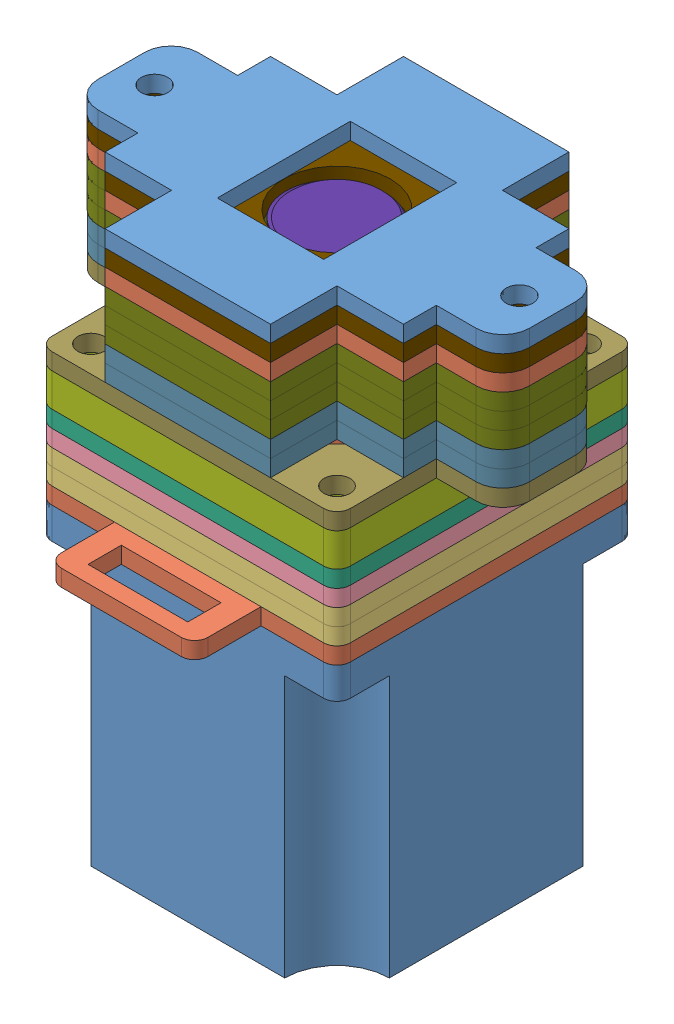
SolidWorks assembly Gearbox, configuration Default. Lengths in mm.
Overall size (82.4 106.8 74.43).
32 component instances, 20 part files, 82 mates.
Components (placement in the parent):
- Stepper-2: Stepper [Default] at (30.9949 23.0878 37.3572) size (57 78.6 57)
- Bottomest Layer-1: Bottomest Layer [Default] at (30.9949 79.0878 37.3572) x (0 0 -1) z (1 0 0) size (69.7 3.17 57)
- Bottom Layer-1: Bottom Layer [Default] at (30.9949 82.2628 37.3572) size (57 3.17 57)
- Bottom Layer-2: Bottom Layer [Default] at (30.9949 85.4378 37.3572) size (57 3.17 57)
- Bottom Middle Layer-1: Bottom Middle Layer [Default] at (30.9949 88.6128 37.3572) size (57 3.17 57)
- Bottom Planet Retainer-1: Bottom Planet Retainer [Default] at (30.9949 91.7878 37.3572) size (50.8 3.17 50.8)
- Bottom Planet Retainer Layer-1: Bottom Planet Retainer Layer [Default] at (30.9949 91.7878 37.3572) size (57 3.17 57)
- Gear-64-1: Gear-64 [Default] at (121.5885 94.9628 50.1488) size (57 6.35 57)
- Gear-24-New-1: Gear-24-New [Default] at (71.8801 101.3128 34.4101) x (1 0 0) z (0 -1 0) size (20.51 20.51 6.35)
- Gear-24-New-2: Gear-24-New [Default] at (87.5193 101.3128 50.0415) x (1 0 0) z (0 -1 0) size (20.51 20.51 6.35)
- Gear-24-New-3: Gear-24-New [Default] at (71.8878 101.3128 65.6808) x (1 0 0) z (0 -1 0) size (20.51 20.51 6.35)
- Gear-24-New-4: Gear-24-New [Default] at (56.2486 101.3128 50.0493) x (1 0 0) z (0 -1 0) size (20.51 20.51 6.35)
- Gear-16-1: Gear-16 [Default] at (42.6663 94.9628 47.2863) x (-1 0 0) z (0 0 -1) size (14.29 6.35 14.29)
- Planet Axle-1: Planet Axle [Default] at (15.3596 94.9628 37.3611) x (0.999996 0 0.002972) z (-0.002972 0 0.999996) size (7.62 9.53 7.62)
- Planet Axle-2: Planet Axle [Default] at (30.991 94.9628 21.7218) x (0.999983 0 0.005817) z (-0.005817 0 0.999983) size (7.62 9.53 7.62)
- Planet Axle-3: Planet Axle [Default] at (46.6303 94.9628 37.3533) x (0.999937 0 -0.011253) z (0.011253 0 0.999937) size (7.62 9.53 7.62)
- Planet Axle-4: Planet Axle [Default] at (30.9988 94.9628 52.9925) x (0.999998 0 -0.001861) z (0.001861 0 0.999998) size (7.62 9.53 7.62)
- Planet Retainer-1: Planet Retainer [Default] at (30.9949 101.3128 37.3572) x (0.706931 0 -0.707283) z (0.707283 0 0.706931) size (46.99 3.17 46.99)
- Middle Layer-1: Middle Layer [Default] at (30.9949 101.3128 37.3572) size (82.4 3.17 57)
- Valve Shaft Engage-1: Valve Shaft Engage [Default] at (30.9949 104.4878 37.3572) x (0.992527 0 -0.122022) z (0.122022 0 0.992527) size (25.4 3.17 25.4)
- Valve Engage Retainer Layer-1: Valve Engage Retainer Layer [Default] at (30.9949 104.4878 37.3572) size (82.4 3.17 57)
- Valve Engage Retainer Layer-2: Valve Engage Retainer Layer [Default] at (30.9949 107.6628 37.3572) size (82.4 3.17 57)
- Valve Shaft Engage Retainer-1: Valve Shaft Engage Retainer [Default] at (30.9949 104.4878 37.3572) size (45.72 3.17 45.72)
- Valve Shaft Engage Retainer-2: Valve Shaft Engage Retainer [Default] at (30.9949 107.6628 37.3572) size (45.72 3.17 45.72)
- Valve Shaft Engage-2: Valve Shaft Engage [Default] at (30.9949 107.6628 37.3572) x (0.992527 0 -0.122022) z (0.122022 0 0.992527) size (25.4 3.17 25.4)
- Top Layer - Valve-2: Top Layer - Valve [Default] at (30.9949 110.8378 37.3572) size (82.4 3.17 57)
- Valve-1: Valve [Default] at (30.9949 112.7617 37.3572) x (-0.992527 0 0.122022) z (0.122022 0 0.992527) size (19.14 21.75 19.92)
- Top Layer - Valve-3: Top Layer - Valve [Default] at (30.9949 114.0128 37.3572) size (82.4 3.17 57)
- Top Layer - Valve-4: Top Layer - Valve [Default] at (30.9949 117.1878 37.3572) size (82.4 3.17 57)
- Top Layer - Valve Interface-1: Top Layer - Valve Interface [Default] at (30.9949 123.5378 37.3572) size (82.4 3.17 57)
- Top Layer - Valve Rotate Lock-1: Top Layer - Valve Rotate Lock [Default] at (30.9949 126.7128 37.3572) size (82.4 3.17 57)
- Top Layer - Valve Nut Lock-1: Top Layer - Valve Nut Lock [Default] at (30.9949 120.3628 37.3572) size (82.4 3.17 57)
Mates (geometry in assembly coordinates):
- Concentric2: concentric anti-aligned: cylinder of Stepper-2 through (54.4949 53.6878 60.8572) axis (0 1 0) radius 2.5; cylinder of Bottomest Layer-1 through (54.4949 82.2628 60.8572) axis (0 -1 0) radius 2.5
- Concentric3: concentric anti-aligned: cylinder of Stepper-2 through (7.4949 53.6878 60.8572) axis (0 1 0) radius 2.5; cylinder of Bottomest Layer-1 through (7.4949 82.2628 60.8572) axis (0 -1 0) radius 2.5
- Concentric7: concentric aligned: cylinder of Bottomest Layer-1 through (54.4949 82.2628 60.8572) axis (0 -1 0) radius 2.5; cylinder of Bottom Layer-1 through (54.4949 85.4378 60.8572) axis (0 -1 0) radius 2.5
- Concentric8: concentric aligned: cylinder of Bottomest Layer-1 through (7.4949 82.2628 60.8572) axis (0 -1 0) radius 2.5; cylinder of Bottom Layer-1 through (7.4949 85.4378 60.8572) axis (0 -1 0) radius 2.5
- Concentric9: concentric aligned: cylinder of Bottom Layer-1 through (7.4949 85.4378 60.8572) axis (0 -1 0) radius 2.5; cylinder of Bottom Layer-2 through (7.4949 88.6128 60.8572) axis (0 -1 0) radius 2.5
- Concentric10: concentric aligned: cylinder of Bottom Layer-1 through (54.4949 85.4378 60.8572) axis (0 -1 0) radius 2.5; cylinder of Bottom Layer-2 through (54.4949 88.6128 60.8572) axis (0 -1 0) radius 2.5
- Coincident1: coincident anti-aligned: plane of Stepper-2 through (30.9949 79.0878 37.3572) normal (0 1 0); plane of Bottomest Layer-1 through (5.0349 79.0878 11.3972) normal (0 -1 0)
- Coincident2: coincident anti-aligned: plane of Bottomest Layer-1 through (5.0349 82.2628 11.3972) normal (0 1 0); plane of Bottom Layer-1 through (56.9549 82.2628 11.3972) normal (0 -1 0)
- Coincident3: coincident anti-aligned: plane of Bottom Layer-1 through (56.9549 85.4378 11.3972) normal (0 1 0); plane of Bottom Layer-2 through (56.9549 85.4378 11.3972) normal (0 -1 0)
- Concentric11: concentric aligned: cylinder of Bottom Layer-2 through (7.4949 88.6128 60.8572) axis (0 -1 0) radius 2.5; cylinder of Bottom Middle Layer-1 through (7.4949 91.7878 60.8572) axis (0 -1 0) radius 2.5
- Concentric12: concentric aligned: cylinder of Bottom Layer-2 through (54.4949 88.6128 60.8572) axis (0 -1 0) radius 2.5; cylinder of Bottom Middle Layer-1 through (54.4949 91.7878 60.8572) axis (0 -1 0) radius 2.5
- Coincident5: coincident anti-aligned: plane of Bottom Layer-2 through (56.9549 88.6128 11.3972) normal (0 1 0); plane of Bottom Middle Layer-1 through (56.9549 88.6128 11.3972) normal (0 -1 0)
- Concentric13: concentric aligned: cylinder of Bottom Middle Layer-1 through (54.4949 91.7878 60.8572) axis (0 -1 0) radius 2.5; cylinder of Bottom Planet Retainer Layer-1 through (54.4949 94.9628 60.8572) axis (0 -1 0) radius 2.5
- Concentric14: concentric aligned: cylinder of Bottom Middle Layer-1 through (7.4949 91.7878 60.8572) axis (0 -1 0) radius 2.5; cylinder of Bottom Planet Retainer Layer-1 through (7.4949 94.9628 60.8572) axis (0 -1 0) radius 2.5
- Coincident6: coincident anti-aligned: plane of Bottom Planet Retainer-1 through (9.0047 94.9628 54.883) normal (-0.706647 0 0.707566); plane of Bottom Planet Retainer Layer-1 through (9.0047 94.9628 54.883) normal (0.706647 0 -0.707566)
- Coincident7: coincident anti-aligned: plane of Bottom Planet Retainer-1 through (48.5207 94.9628 59.3474) normal (0.707566 0 0.706647); plane of Bottom Planet Retainer Layer-1 through (48.5207 94.9628 59.3474) normal (-0.707566 0 -0.706647)
- Coincident8: coincident aligned: plane of Bottom Planet Retainer-1 through (30.9949 94.9628 37.3572) normal (0 1 0); plane of Bottom Planet Retainer Layer-1 through (56.9549 94.9628 11.3972) normal (0 1 0)
- Coincident9: coincident anti-aligned: plane of Bottom Middle Layer-1 through (56.9549 91.7878 11.3972) normal (0 1 0); plane of Bottom Planet Retainer Layer-1 through (56.9549 91.7878 11.3972) normal (0 -1 0)
- Concentric16: concentric aligned: cylinder of Bottom Planet Retainer Layer-1 through (7.4949 94.9628 60.8572) axis (0 -1 0) radius 2.5; cylinder of Gear-64-1 through (7.4949 101.3128 60.8572) axis (0 -1 0) radius 2.5
- Concentric17: concentric aligned: cylinder of Bottom Planet Retainer Layer-1 through (54.4949 94.9628 60.8572) axis (0 -1 0) radius 2.5; cylinder of Gear-64-1 through (54.4949 101.3128 60.8572) axis (0 -1 0) radius 2.5
- Coincident10: coincident anti-aligned: plane of Bottom Planet Retainer Layer-1 through (56.9549 94.9628 11.3972) normal (0 1 0); plane of Gear-64-1 through (5.0349 94.9628 63.3172) normal (0 -1 0)
- Coincident17: coincident aligned: plane of Gear-64-1 through (5.0349 101.3128 63.3172) normal (0 1 0); plane of Gear-24-New-4 through (13.2871 101.3128 33.3946) normal (0 1 0)
- Coincident18: coincident aligned: plane of Gear-64-1 through (5.0349 101.3128 63.3172) normal (0 1 0); plane of Gear-24-New-1 through (28.9185 101.3128 17.7553) normal (0 1 0)
- Coincident19: coincident aligned: plane of Gear-64-1 through (5.0349 101.3128 63.3172) normal (0 1 0); plane of Gear-24-New-2 through (44.5578 101.3128 33.3868) normal (0 1 0)
- Coincident20: coincident aligned: plane of Gear-64-1 through (5.0349 101.3128 63.3172) normal (0 1 0); plane of Gear-24-New-3 through (28.9263 101.3128 49.0261) normal (0 1 0)
- Coincident21: coincident anti-aligned: plane of Stepper-2 through (32.7052 86.6878 40.0322) normal (0 0 1); plane of Gear-16-1 through (32.7052 101.3128 40.0322) normal (0 0 -1)
- Concentric18: concentric aligned: cylinder of Stepper-2 through (30.9949 101.6878 37.3572) axis (0 -1 0) radius 3.175; cylinder of Gear-16-1 through (30.9949 101.3128 37.3572) axis (0 -1 0) radius 3.175
- Coincident22: coincident aligned: plane of Gear-64-1 through (5.0349 101.3128 63.3172) normal (0 1 0); plane of Gear-16-1 through (31.1794 101.3128 34.3794) normal (0 1 0)
- Concentric19: concentric anti-aligned: cylinder of Gear-24-New-4 through (15.3596 94.9628 37.3611) axis (0 1 0) radius 3.81; cylinder of Planet Axle-1 through (15.3596 104.4878 37.3611) axis (0 -1 0) radius 3.81
- Concentric20: concentric anti-aligned: cylinder of Gear-24-New-1 through (30.991 94.9628 21.7218) axis (0 1 0) radius 3.81; cylinder of Planet Axle-2 through (30.991 104.4878 21.7218) axis (0 -1 0) radius 3.81
- Concentric21: concentric anti-aligned: cylinder of Gear-24-New-2 through (46.6303 94.9628 37.3533) axis (0 1 0) radius 3.81; cylinder of Planet Axle-3 through (46.6303 104.4878 37.3533) axis (0 -1 0) radius 3.81
- Concentric22: concentric anti-aligned: cylinder of Gear-24-New-3 through (30.9988 94.9628 52.9925) axis (0 1 0) radius 3.81; cylinder of Planet Axle-4 through (30.9988 104.4878 52.9925) axis (0 -1 0) radius 3.81
- Coincident23: coincident anti-aligned: plane of Bottom Planet Retainer-1 through (30.9949 94.9628 37.3572) normal (0 1 0); plane of Planet Axle-1 through (15.3596 94.9628 37.3611) normal (0 -1 0)
- Coincident24: coincident anti-aligned: plane of Bottom Planet Retainer-1 through (30.9949 94.9628 37.3572) normal (0 1 0); plane of Planet Axle-4 through (30.9988 94.9628 52.9925) normal (0 -1 0)
- Coincident25: coincident anti-aligned: plane of Bottom Planet Retainer-1 through (30.9949 94.9628 37.3572) normal (0 1 0); plane of Planet Axle-3 through (46.6303 94.9628 37.3533) normal (0 -1 0)
- Coincident26: coincident anti-aligned: plane of Bottom Planet Retainer-1 through (30.9949 94.9628 37.3572) normal (0 1 0); plane of Planet Axle-2 through (30.991 94.9628 21.7218) normal (0 -1 0)
- Concentric23: concentric aligned: cylinder of Stepper-2 through (30.9949 101.6878 37.3572) axis (0 -1 0) radius 3.175; cylinder of Planet Retainer-1 through (30.9949 104.4878 37.3572) axis (0 -1 0) radius 3.556
- Coincident27: coincident anti-aligned: plane of Gear-64-1 through (5.0349 101.3128 63.3172) normal (0 1 0); plane of Planet Retainer-1 through (30.9949 101.3128 37.3572) normal (0 -1 0)
- Concentric24: concentric aligned: cylinder of Planet Axle-1 through (15.3596 104.4878 37.3611) axis (0 -1 0) radius 3.81; cylinder of Planet Retainer-1 through (15.3596 104.4878 37.3611) axis (0 -1 0) radius 3.81
- Concentric25: concentric aligned: cylinder of Planet Axle-2 through (30.991 104.4878 21.7218) axis (0 -1 0) radius 3.81; cylinder of Planet Retainer-1 through (30.991 104.4878 21.7218) axis (0 -1 0) radius 3.81
- Concentric26: concentric aligned: cylinder of Planet Axle-3 through (46.6303 104.4878 37.3533) axis (0 -1 0) radius 3.81; cylinder of Planet Retainer-1 through (46.6303 104.4878 37.3533) axis (0 -1 0) radius 3.81
- Concentric27: concentric aligned: cylinder of Planet Axle-4 through (30.9988 104.4878 52.9925) axis (0 -1 0) radius 3.81; cylinder of Planet Retainer-1 through (30.9988 104.4878 52.9925) axis (0 -1 0) radius 3.81
- Concentric28: concentric aligned: cylinder of Gear-64-1 through (7.4949 101.3128 60.8572) axis (0 -1 0) radius 2.5; cylinder of Middle Layer-1 through (7.4949 104.4878 60.8572) axis (0 -1 0) radius 2.5
- Concentric29: concentric aligned: cylinder of Gear-64-1 through (54.4949 101.3128 60.8572) axis (0 -1 0) radius 2.5; cylinder of Middle Layer-1 through (54.4949 104.4878 60.8572) axis (0 -1 0) radius 2.5
- Coincident28: coincident anti-aligned: plane of Gear-64-1 through (5.0349 101.3128 63.3172) normal (0 1 0); plane of Middle Layer-1 through (56.9549 101.3128 11.3972) normal (0 -1 0)
- Concentric30: concentric anti-aligned: circle of Planet Retainer-1; cylinder of Valve Shaft Engage-1 through (30.9949 107.6628 37.3572) axis (0 -1 0) radius 2.6
- Coincident29: coincident anti-aligned: plane of Planet Retainer-1 through (30.9949 104.4878 37.3572) normal (0 1 0); plane of Valve Shaft Engage-1 through (30.9949 104.4878 37.3572) normal (0 -1 0)
- Concentric31: concentric aligned: cylinder of Middle Layer-1 through (-3.8551 104.4878 37.3572) axis (0 -1 0) radius 2.54; cylinder of Valve Engage Retainer Layer-1 through (-3.8551 107.6628 37.3572) axis (0 -1 0) radius 2.54
- Concentric32: concentric aligned: cylinder of Middle Layer-1 through (65.8449 104.4878 37.3572) axis (0 -1 0) radius 2.54; cylinder of Valve Engage Retainer Layer-1 through (65.8449 107.6628 37.3572) axis (0 -1 0) radius 2.54
- Coincident30: coincident anti-aligned: plane of Middle Layer-1 through (56.9549 104.4878 11.3972) normal (0 1 0); plane of Valve Engage Retainer Layer-1 through (-5.1251 104.4878 32.9122) normal (0 -1 0)
- Coincident31: coincident anti-aligned: plane of Valve Engage Retainer Layer-1 through (34.1699 107.6628 60.2172) normal (0 0 -1); plane of Valve Shaft Engage Retainer-1 through (34.1699 107.6628 60.2172) normal (0 0 1)
- Coincident32: coincident anti-aligned: plane of Valve Engage Retainer Layer-1 through (8.1349 107.6628 40.5322) normal (1 0 0); plane of Valve Shaft Engage Retainer-1 through (8.1349 107.6628 40.5322) normal (-1 0 0)
- Coincident33: coincident anti-aligned: plane of Planet Retainer-1 through (30.9949 104.4878 37.3572) normal (0 1 0); plane of Valve Shaft Engage Retainer-1 through (30.9949 104.4878 37.3572) normal (0 -1 0)
- Concentric33: concentric aligned: cylinder of Valve Engage Retainer Layer-1 through (-3.8551 107.6628 37.3572) axis (0 -1 0) radius 2.54; cylinder of Valve Engage Retainer Layer-2 through (-3.8551 110.8378 37.3572) axis (0 -1 0) radius 2.54
- Concentric34: concentric aligned: cylinder of Valve Engage Retainer Layer-1 through (65.8449 107.6628 37.3572) axis (0 -1 0) radius 2.54; cylinder of Valve Engage Retainer Layer-2 through (65.8449 110.8378 37.3572) axis (0 -1 0) radius 2.54
- Coincident34: coincident anti-aligned: plane of Valve Engage Retainer Layer-1 through (-5.1251 107.6628 32.9122) normal (0 1 0); plane of Valve Engage Retainer Layer-2 through (-5.1251 107.6628 32.9122) normal (0 -1 0)
- Coincident36: coincident anti-aligned: plane of Valve Engage Retainer Layer-2 through (34.1699 110.8378 60.2172) normal (0 0 -1); plane of Valve Shaft Engage Retainer-2 through (34.1699 110.8378 60.2172) normal (0 0 1)
- Coincident37: coincident anti-aligned: plane of Valve Engage Retainer Layer-2 through (8.1349 110.8378 40.5322) normal (1 0 0); plane of Valve Shaft Engage Retainer-2 through (8.1349 110.8378 40.5322) normal (-1 0 0)
- Coincident38: coincident anti-aligned: plane of Valve Shaft Engage Retainer-1 through (30.9949 107.6628 37.3572) normal (0 1 0); plane of Valve Shaft Engage Retainer-2 through (30.9949 107.6628 37.3572) normal (0 -1 0)
- Coincident39: coincident aligned: plane of Valve Shaft Engage-1 through (29.0455 107.6628 35.6369) normal (0.122022 0 0.992527); plane of Valve Shaft Engage-2 through (29.0455 110.8378 35.6369) normal (0.122022 0 0.992527)
- Concentric35: concentric aligned: cylinder of Valve Shaft Engage-1 through (30.9949 107.6628 37.3572) axis (0 -1 0) radius 2.6; cylinder of Valve Shaft Engage-2 through (30.9949 110.8378 37.3572) axis (0 -1 0) radius 2.6
- Coincident40: coincident anti-aligned: plane of Valve Shaft Engage-1 through (30.9949 107.6628 37.3572) normal (0 1 0); plane of Valve Shaft Engage-2 through (30.9949 107.6628 37.3572) normal (0 -1 0)
- Concentric36: concentric aligned: cylinder of Valve Engage Retainer Layer-2 through (-3.8551 110.8378 37.3572) axis (0 -1 0) radius 2.54; cylinder of Top Layer - Valve-2 through (-3.8551 114.0128 37.3572) axis (0 -1 0) radius 2.54
- Concentric37: concentric aligned: cylinder of Valve Engage Retainer Layer-2 through (65.8449 110.8378 37.3572) axis (0 -1 0) radius 2.54; cylinder of Top Layer - Valve-2 through (65.8449 114.0128 37.3572) axis (0 -1 0) radius 2.54
- Coincident41: coincident anti-aligned: plane of Valve Engage Retainer Layer-2 through (-5.1251 110.8378 32.9122) normal (0 1 0); plane of Top Layer - Valve-2 through (-5.1251 110.8378 32.9122) normal (0 -1 0)
- Coincident42: coincident anti-aligned: plane of Valve Shaft Engage-2 through (29.8623 110.8378 39.6975) normal (-0.122022 0 -0.992527); plane of Valve-1 through (32.6607 104.7617 39.3535) normal (0.122022 0 0.992527)
- Concentric38: concentric anti-aligned: cylinder of Valve Shaft Engage-2 through (30.9949 110.8378 37.3572) axis (0 -1 0) radius 2.6; cylinder of Valve-1 through (30.9949 104.7617 37.3572) axis (0 1 0) radius 2.6
- Concentric39: concentric aligned: cylinder of Top Layer - Valve-2 through (-3.8551 114.0128 37.3572) axis (0 -1 0) radius 2.54; cylinder of Top Layer - Valve-3 through (-3.8551 117.1878 37.3572) axis (0 -1 0) radius 2.54
- Concentric40: concentric aligned: cylinder of Top Layer - Valve-2 through (65.8449 114.0128 37.3572) axis (0 -1 0) radius 2.54; cylinder of Top Layer - Valve-3 through (65.8449 117.1878 37.3572) axis (0 -1 0) radius 2.54
- Coincident43: coincident anti-aligned: plane of Top Layer - Valve-2 through (-5.1251 114.0128 32.9122) normal (0 1 0); plane of Top Layer - Valve-3 through (-5.1251 114.0128 32.9122) normal (0 -1 0)
- Coincident44: coincident anti-aligned: plane of Top Layer - Valve-3 through (-5.1251 117.1878 32.9122) normal (0 1 0); plane of Top Layer - Valve-4 through (-5.1251 117.1878 32.9122) normal (0 -1 0)
- Concentric41: concentric aligned: cylinder of Top Layer - Valve-3 through (65.8449 117.1878 37.3572) axis (0 -1 0) radius 2.54; cylinder of Top Layer - Valve-4 through (65.8449 120.3628 37.3572) axis (0 -1 0) radius 2.54
- Concentric42: concentric aligned: cylinder of Top Layer - Valve-3 through (-3.8551 117.1878 37.3572) axis (0 -1 0) radius 2.54; cylinder of Top Layer - Valve-4 through (-3.8551 120.3628 37.3572) axis (0 -1 0) radius 2.54
- Concentric47: concentric aligned: cylinder of Top Layer - Valve Interface-1 through (-3.8551 152.7697 37.3572) axis (0 -1 0) radius 2.54; cylinder of Top Layer - Valve Rotate Lock-1 through (-3.8551 155.9447 37.3572) axis (0 -1 0) radius 2.54
- Concentric48: concentric aligned: cylinder of Top Layer - Valve Interface-1 through (65.8449 152.7697 37.3572) axis (0 -1 0) radius 2.54; cylinder of Top Layer - Valve Rotate Lock-1 through (65.8449 155.9447 37.3572) axis (0 -1 0) radius 2.54
- Coincident47: coincident anti-aligned: plane of Top Layer - Valve Interface-1 through (-5.1251 152.7697 32.9122) normal (0 1 0); plane of Top Layer - Valve Rotate Lock-1 through (-5.1251 152.7697 32.9122) normal (0 -1 0)
- Concentric49: concentric aligned: cylinder of Top Layer - Valve-4 through (-3.8551 120.3628 37.3572) axis (0 -1 0) radius 2.54; cylinder of Top Layer - Valve Nut Lock-1 through (-3.8551 123.5378 37.3572) axis (0 -1 0) radius 2.54
- Concentric50: concentric aligned: cylinder of Top Layer - Valve-4 through (65.8449 120.3628 37.3572) axis (0 -1 0) radius 2.54; cylinder of Top Layer - Valve Nut Lock-1 through (65.8449 123.5378 37.3572) axis (0 -1 0) radius 2.54
- Concentric51: concentric aligned: cylinder of Top Layer - Valve Interface-1 through (-3.8551 126.7128 37.3572) axis (0 -1 0) radius 2.54; cylinder of Top Layer - Valve Nut Lock-1 through (-3.8551 123.5378 37.3572) axis (0 -1 0) radius 2.54
- Concentric52: concentric aligned: cylinder of Top Layer - Valve Interface-1 through (65.8449 126.7128 37.3572) axis (0 -1 0) radius 2.54; cylinder of Top Layer - Valve Nut Lock-1 through (65.8449 123.5378 37.3572) axis (0 -1 0) radius 2.54
- Coincident48: coincident anti-aligned: plane of Top Layer - Valve-4 through (-5.1251 120.3628 32.9122) normal (0 1 0); plane of Top Layer - Valve Nut Lock-1 through (-5.1251 120.3628 32.9122) normal (0 -1 0)
- Coincident49: coincident anti-aligned: plane of Top Layer - Valve Interface-1 through (-5.1251 123.5378 32.9122) normal (0 -1 0); plane of Top Layer - Valve Nut Lock-1 through (-5.1251 123.5378 32.9122) normal (0 1 0)
